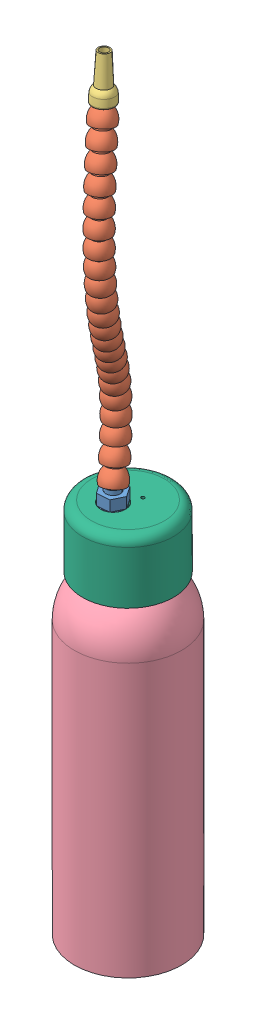
SolidWorks assembly _Robocup_Assembly_Thermos_Static_, configuration Default. Lengths in mm.
Overall size (75.21 554.8 95.58).
28 component instances, 6 part files, 9 mates.
Components (placement in the parent):
- Coolant Pipe.stp-1: Coolant Pipe.stp [Default] at (-3.81 14.5 6.5991) x (0.568385 0 0.822762) z (-0.822762 0 0.568385) size (74.23 300.91 26.18)
  - Coolant Bolt.stp-1: Coolant Bolt.stp [Default] x (-1 0 0) z (0 0 1) size (17.61 27.5 15.25)
  - Connectors.stp-1: Connectors.stp [Default] at (-2.2835 3.6671 -0.0362) x (-0.321951 -0.100327 -0.941426) z (0.285439 -0.958386 0.00452) size (18.3 18.3 20)
  - Connectors.stp-2: Connectors.stp [Default] at (-0.9485 62.1668 -0.2193) x (0.834188 -0.338799 0.435138) z (-0.378337 -0.925657 0.00458) size (18.3 18.3 20)
  - Connectors.stp-3: Connectors.stp [Default] at (-7.0218 39.1054 -0.1142) x (0.974617 -0.052931 0.217534) z (-0.054998 -0.99848 0.003454) size (18.3 18.3 20)
  - Connectors.stp-4: Connectors.stp [Default] at (-7.018 27.1423 -0.0887) x (-0.288884 -0.031731 -0.956838) z (0.11095 -0.993826 -0.00054) size (18.3 18.3 20)
  - Connectors.stp-5: Connectors.stp [Default] at (10.0914 83.4503 -0.3173) x (0.525964 -0.304704 -0.794051) z (-0.497138 -0.867664 0.003658) size (18.3 18.3 20)
  - Connectors.stp-6: Connectors.stp [Default] at (4.2645 72.9625 -0.2712) x (0.886562 -0.462353 0.015441) z (-0.462461 -0.88663 0.004202) size (18.3 18.3 20)
  - Connectors.stp-7: Connectors.stp [Default] at (-4.9174 50.8742 -0.1644) x (0.803108 -0.192004 0.56405) z (-0.235547 -0.971852 0.004557) size (18.3 18.3 20)
  - Connectors.stp-8: Connectors.stp [Default] at (16.0513 93.8656 -0.3564) x (0.86534 -0.495122 -0.077724) z (-0.496415 -0.86808 0.003062) size (18.3 18.3 20)
  - Connectors.stp-9: Connectors.stp [Default] at (35.5838 137.5772 -0.4345) x (0.770438 -0.236558 0.592002) z (-0.293738 -0.955886 0.000312) size (18.3 18.3 20)
  - Connectors.stp-10: Connectors.stp [Default] at (38.4122 149.228 -0.4322) x (0.672162 -0.141658 -0.726727) z (-0.20668 -0.978409 -0.000445) size (18.3 18.3 20)
  - Connectors.stp-11: Connectors.stp [Default] at (31.7619 126.2108 -0.4277) x (0.912958 -0.361121 0.189996) z (-0.368012 -0.929821 0.001063) size (18.3 18.3 20)
  - Connectors.stp-12: Connectors.stp [Default] at (21.8052 104.3949 -0.3882) x (-0.461711 0.244191 -0.852756) z (-0.471034 -0.882112 0.002437) size (18.3 18.3 20)
  - Connectors.stp-13: Connectors.stp [Default] at (-5.2287 15.2947 -0.0801) x (0.757626 0.173214 -0.629285) z (0.225426 -0.974255 0.003232) size (18.3 18.3 20)
  - Connectors.stp-14: Connectors.stp [Default] at (27.1083 115.1559 -0.4121) x (0.901968 -0.4265 -0.067469) z (-0.427365 -0.904078 0.001774) size (18.3 18.3 20)
  - Coolant Pipe Nozzle.stp-1: Coolant Pipe Nozzle.stp [Default] at (27.898 246.6708 -0.2231) x (-0.153795 -0.02183 0.987862) z (0.098368 -0.995128 -0.006677) size (15 15 30)
  - Connectors.stp-15: Connectors.stp [Default] at (40.4307 185.0487 -0.3789) x (0.938856 0.053217 -0.340172) z (0.055817 -0.998439 -0.002147) size (18.3 18.3 20)
  - Connectors.stp-16: Connectors.stp [Default] at (39.2092 196.9799 -0.3507) x (0.937442 0.118696 -0.327281) z (0.124773 -0.992182 -0.002445) size (18.3 18.3 20)
  - Connectors.stp-17: Connectors.stp [Default] at (40.784 173.0623 -0.4029) x (0.972219 -0.02226 -0.233011) z (-0.023301 -0.999727 -0.001718) size (18.3 18.3 20)
  - Connectors.stp-18: Connectors.stp [Default] at (40.1447 161.0902 -0.4212) x (0.882181 -0.100002 -0.460169) z (-0.113225 -0.993569 -0.001143) size (18.3 18.3 20)
  - Connectors.stp-19: Connectors.stp [Default] at (31.9646 232.2183 -0.2574) x (0.793284 0.199128 0.575369) z (0.245233 -0.969461 -0.002594) size (18.3 18.3 20)
  - Connectors.stp-20: Connectors.stp [Default] at (37.2637 208.8167 -0.3201) x (0.26581 0.051415 -0.962653) z (0.180811 -0.983514 -0.002604) size (18.3 18.3 20)
  - Connectors.stp-21: Connectors.stp [Default] at (28.861 243.8093 -0.2266) x (0.725081 0.197806 0.659645) z (0.26534 -0.964151 -0.002545) size (18.3 18.3 20)
  - Connectors.stp-22: Connectors.stp [Default] at (34.7978 220.5587 -0.2886) x (0.975424 0.217793 -0.033387) z (0.217828 -0.975984 -0.002632) size (18.3 18.3 20)
- Thermos-1: Thermos [Default] at (0 -262.89 0) size (74.93 250.19 74.93)
- 51235K107_Push-to-Connect Tube Fitting with Universal Thread-2: 51235K107_Push-to-Connect Tube Fitting with Universal Thread [51235K107] at (-3.81 -31.88 6.5991) x (0 1 0) z (0.852121 0 -0.523345) size (19.14 14.66 12.7)
- Robocup_Lid_Thermos_Static-1: Robocup_Lid_Thermos_Static [Default] at (0 -44.45 0) size (63.5 43.72 63.5)
Mates (geometry in assembly coordinates):
- Coincident1: coincident aligned: plane of Thermos-1 through (0 -262.89 0) normal (0 0 1)
- Coincident2: coincident aligned: plane of Thermos-1 through (0 -262.89 0) normal (1 0 0)
- Coincident3: coincident anti-aligned: plane of 51235K107_Push-to-Connect Tube Fitting with Universal Thread-2 through (-3.81 -17.78 6.5991) normal (0 1 0); plane of Robocup_Lid_Thermos_Static-1 through (0 -17.78 0) normal (0 -1 0)
- Concentric1: concentric anti-aligned: cylinder of 51235K107_Push-to-Connect Tube Fitting with Universal Thread-2 through (-3.81 -31.88 6.5991) axis (0 -1 0) radius 5; cylinder of Robocup_Lid_Thermos_Static-1 through (-3.81 -43.18 6.5991) axis (0 1 0) radius 3.556
- Coincident4: coincident aligned: plane of Robocup_Lid_Thermos_Static-1 through (0 0 0) normal (0 1 0)
- Concentric2: concentric anti-aligned: cylinder of Thermos-1 through (0 -262.89 0) axis (0 -1 0) radius 24.384; cylinder of Robocup_Lid_Thermos_Static-1 through (0 -43.18 0) axis (0 1 0) radius 31.75
- Coincident5: coincident anti-aligned: plane of Thermos-1 through (24.384 -12.7 0) normal (0 1 0); plane of Robocup_Lid_Thermos_Static-1 through (0 -12.7 0) normal (0 -1 0)
- Concentric3: concentric aligned: cylinder of Coolant Pipe.stp-1/Coolant Bolt.stp-1 through (-3.81 9 6.5991) axis (0 1 0) radius 5; cylinder of Robocup_Lid_Thermos_Static-1 through (-3.81 -43.18 6.5991) axis (0 1 0) radius 3.556
- Coincident6: coincident anti-aligned: plane of Coolant Pipe.stp-1/Coolant Bolt.stp-1 through (-3.81 0 6.5991) normal (0 -1 0); plane of Robocup_Lid_Thermos_Static-1 through (0 0 0) normal (0 1 0)
